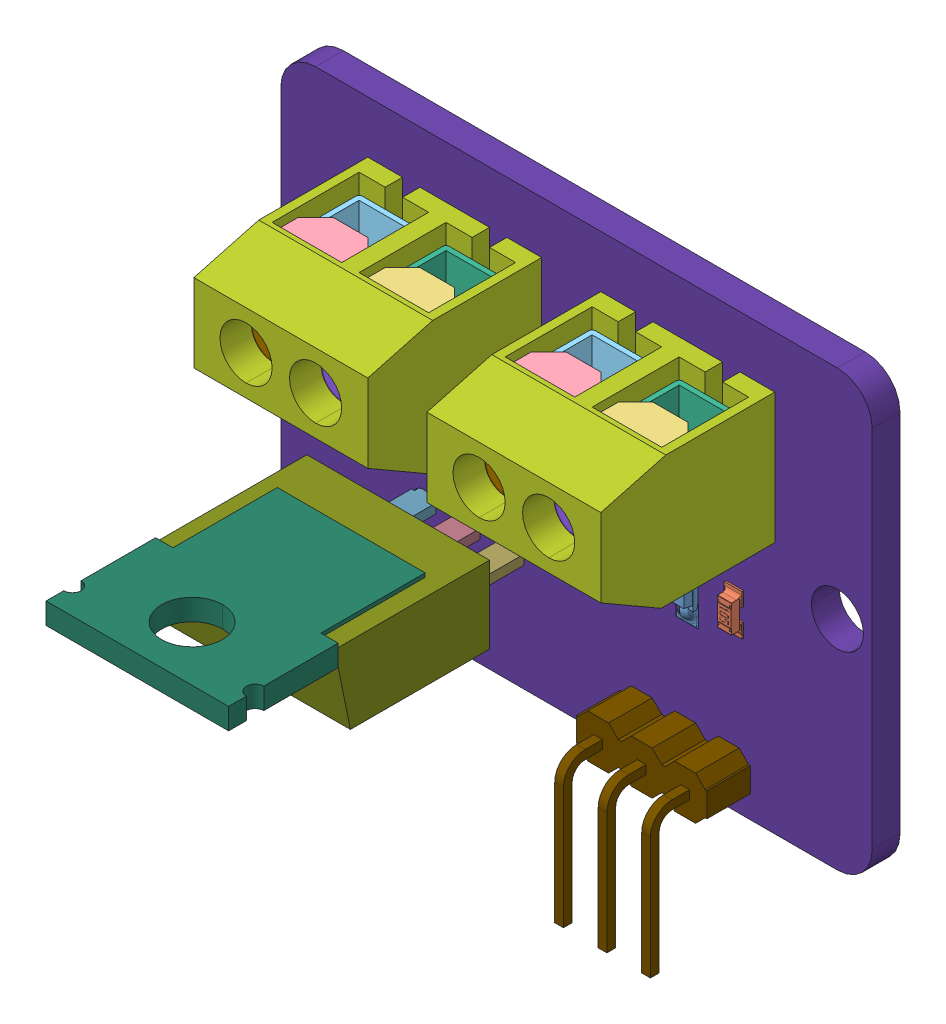
SolidWorks assembly irf520n_module_asm, configuration Default. Lengths in mm.
Overall size (34 31 21.5).
33 component instances, 20 part files, 0 mates.
Components (placement in the parent):
- irf520n_module_asm.stp-1: irf520n_module_asm.stp [Default] at origin size (34 31 21.5)
  - CONECTOR_2X_AF0_ASM.stp-1: CONECTOR_2X_AF0_ASM.stp [Default] at (10.0021 9.5092 -1.5) x (1 0 0) z (0 -1 0) size (10 12.5 7.5)
    - CONEC1_AF0.stp-1: CONEC1_AF0.stp [Default] at origin size (0.5 1 0.5)
    - CONEC2_AF0.stp-1: CONEC2_AF0.stp [Default] at origin size (0.5 1 0.5)
    - CONEC3.stp-1: CONEC3.stp [Default] at origin size (4 2.5 0.5)
    - CONEC4.stp-1: CONEC4.stp [Default] at origin size (4 2.5 0.5)
    - CONEC5.stp-1: CONEC5.stp [Default] at origin size (3.8 3.8 4)
    - CONEC6.stp-1: CONEC6.stp [Default] at origin size (3.8 3.8 4)
    - CONEC7.stp-1: CONEC7.stp [Default] at origin size (10 10 7.5)
    - CONEC8.stp-1: CONEC8.stp [Default] at origin size (2.6 2.5 2.6)
    - CONEC9.stp-1: CONEC9.stp [Default] at origin size (2.6 2.5 2.6)
  - CONECTOR_2X_AF1_ASM.stp-1: CONECTOR_2X_AF1_ASM.stp [Default] at (23.4021 9.5092 -1.5) x (1 0 0) z (0 -1 0) size (10 12.5 7.5)
    - CONEC1_AF1.stp-1: CONEC1_AF1.stp [Default] at origin size (0.5 1 0.5)
    - CONEC2_AF1.stp-1: CONEC2_AF1.stp [Default] at origin size (0.5 1 0.5)
    - CONEC3.stp-1: CONEC3.stp [Default] at origin size (4 2.5 0.5)
    - CONEC4.stp-1: CONEC4.stp [Default] at origin size (4 2.5 0.5)
    - CONEC5.stp-1: CONEC5.stp [Default] at origin size (3.8 3.8 4)
    - CONEC6.stp-1: CONEC6.stp [Default] at origin size (3.8 3.8 4)
    - CONEC7.stp-1: CONEC7.stp [Default] at origin size (10 10 7.5)
    - CONEC8.stp-1: CONEC8.stp [Default] at origin size (2.6 2.5 2.6)
    - CONEC9.stp-1: CONEC9.stp [Default] at origin size (2.6 2.5 2.6)
  - IRF520_AF0_ASM.stp-1: IRF520_AF0_ASM.stp [Default] at (16.0021 9.4375 4) x (0 1 0) z (0 0 1) size (4.75 10.5 21.5)
    - IRF3808_1_AF0_ASM.stp-1: IRF3808_1_AF0_ASM.stp [Default] at origin size (0.55 3.94 6.5)
      - IRF3808_1_1_AF0.stp-1: IRF3808_1_1_AF0.stp [Default] at origin size (0.55 1.4 6.5)
      - IRF3808_1_2_AF0.stp-1: IRF3808_1_2_AF0.stp [Default] at origin size (0.55 1.4 6.5)
    - IRF3808_2_AF0.stp-1: IRF3808_2_AF0.stp [Default] at origin size (0.55 1.4 6.5)
    - IRF3808_3.stp-1: IRF3808_3.stp [Default] at origin size (1.22 10.5 12.3)
    - IRF3808_4.stp-1: IRF3808_4.stp [Default] at origin size (4.53 10.5 8.7)
  - IRF520N.stp-1: IRF520N.stp [Default] at origin size (34 25 1.6)
  - ______________6_AF0.stp-1: ______________6_AF0.stp [Default] at (23.2521 9.2592 -1.5) x (0 1 0) z (1 0 0) size (9.25 7.25 7.5)
  - LED.stp-1: LED.stp [Default] at (23.3771 10.0092 0) x (0 1 0) z (1 0 0) size (4.01 1.01 1.32)
  - 603_RESISTOR.stp-1: 603_RESISTOR.stp [Default] at (20.6021 10.0463 0) x (0 -1 0) z (-1 0 0) size (2.36 0.61 1.02)
  - 603_RESISTOR.stp-2: 603_RESISTOR.stp [Default] at (26.1021 10.0463 0) x (0 -1 0) z (-1 0 0) size (2.36 0.61 1.02)
